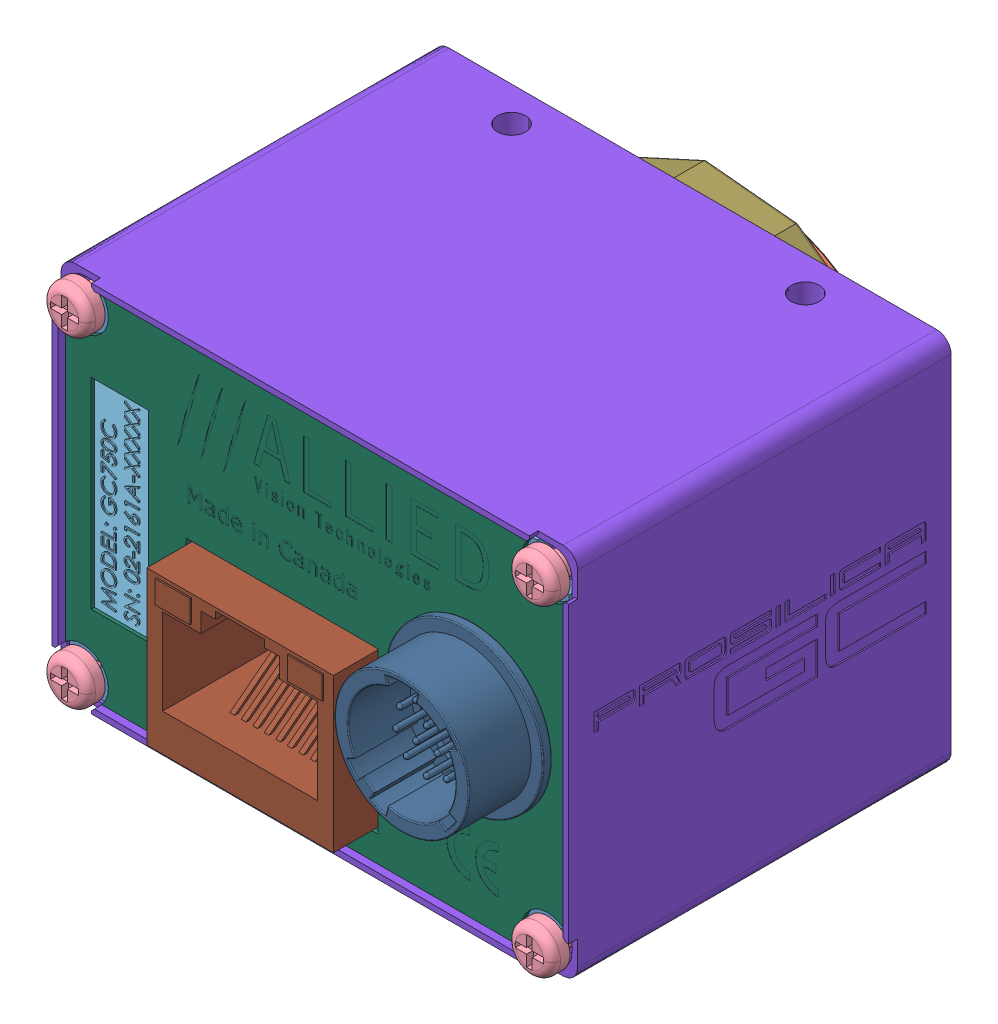
SolidWorks assembly Prosilica_GC750C, configuration Default. Lengths in mm.
Overall size (45.72 40.39 45.39).
25 component instances, 15 part files, 0 mates.
Components (placement in the parent):
- 110043A GC BACK PLATE-1: 110043A GC BACK PLATE [Default] at origin size (44.2 31.5 1.29)
  - 110043A GC BACK PLATE - WO HW-1: 110043A GC BACK PLATE - WO HW [Default] at origin size (44.2 31.5 1.29)
- 110039A-C ADJUSTABLE CS MOUNT RING-1: 110039A-C ADJUSTABLE CS MOUNT RING [Default] at (0 0 -28.7749) x (-0.743279 -0.668982 0) z (0 0 -1) size (27.78 27.78 8.64)
- 140018-SCREW PAN M2x8 SS-1: 140018-SCREW PAN M2x8 SS [Default] at (-17.145 0 -28.0747) x (-0.962983 0.269563 0) z (0 0 -1) size (4 4 9.7)
- 140017-SCREW PAN M2x4 SS-1: 140017-SCREW PAN M2x4 SS [Default] at (20.574 14.224 1.6713) size (4 4 5.6)
- 140018-SCREW PAN M2x8 SS-2: 140018-SCREW PAN M2x8 SS [Default] at (17.145 0 -28.0747) x (-0.840364 0.542023 0) z (0 0 -1) size (4 4 9.7)
- 740070AA-GC750C LABEL PRINT-1: 740070AA-GC750C LABEL PRINT [Default] at (-17.5822 0 1.2903) x (0 1 0) z (0 0 1) size (18.8 6.1 0.2)
- 100097A-IR FILTER ASSEMBLY 0.75 INCH-1: 100097A-IR FILTER ASSEMBLY 0.75 INCH [Default] at (0 0 -31.0392) x (-0.299434 -0.954117 0) z (0 0 -1) size (25.4 25.4 2.54)
  - 440002-IR CUT FILTER 22MM DIA-1: 440002-IR CUT FILTER 22MM DIA [Default] at (0 0 0.27) size (22 22 1)
  - 110054AB-IR FILTER SUPPORT-1: 110054AB-IR FILTER SUPPORT [Default] at origin size (25.4 25.4 2.54)
- 110047B-GC-CMOS FRONT_Finished with logo-1: 110047B-GC-CMOS FRONT_Finished with logo [Default] at (0 0 -31.7747) size (45.72 33.02 33.85)
- 140013-washer spring lock M2-1: 140013-washer spring lock M2 [Default] at (17.145 0 -28.0747) size (4.39 4.4 0.5)
- 260034-HIROSE HR10A-10R-12PB-1: 260034-HIROSE HR10A-10R-12PB [Default] at (13.97 0 2.4613) x (-1 0 0) z (0 0 -1) size (14 14 15.61)
- 140017-SCREW PAN M2x4 SS-2: 140017-SCREW PAN M2x4 SS [Default] at (-20.574 -14.224 1.6713) size (4 4 5.6)
- 200047A-A GC INTERFACE PCB ASSY-1: 200047A-A GC INTERFACE PCB ASSY [Default] at (0 0 -11.2845) size (18.29 13.59 19.94)
  - 260033-AMPHENOL RJHS-3381-1: 260033-AMPHENOL RJHS-3381 [Default] at (-2.921 -13.1445 8.7249) x (0 0 -1) z (0 1 0) size (19.94 18.29 13.59)
- 110040A-B LOCKING RING CS MOUNT-1: 110040A-B LOCKING RING CS MOUNT [Default] at (0 0 -31.7747) x (-0.909526 -0.415646 0) z (0 0 -1) size (30.48 30.48 3.81)
- 140017-SCREW PAN M2x4 SS-3: 140017-SCREW PAN M2x4 SS [Default] at (20.574 -14.224 1.6713) size (4 4 5.6)
- 140017-SCREW PAN M2x4 SS-4: 140017-SCREW PAN M2x4 SS [Default] at (-20.574 14.224 1.6713) size (4 4 5.6)
- 200020BA-PCB ASSEMBLY EC750C SENSOR-with sensor-1: 200020BA-PCB ASSEMBLY EC750C SENSOR-with sensor [Default] at (0 0 -23.6467) size (9 9 1.25)
  - 220046-MICRON MT9V022177ATC-1: 220046-MICRON MT9V022177ATC [Default] at (0 0 -0.3) x (1 0 0) z (0 0 -1) size (9 9 1.25)
    - MT9V022 WINDOW-1: MT9V022 WINDOW [Default] at (0 0 0.55) size (6.7 6.7 0.4)
    - MT9V022 PACKAGE-1: MT9V022 PACKAGE [Default] at origin size (9 9 1.25)
- 740032B-GC MAIN LABEL-1: 740032B-GC MAIN LABEL [Default] at (0 0 1.2903) size (44.2 31.5 0.38)
- 140013-washer spring lock M2-2: 140013-washer spring lock M2 [Default] at (-17.145 0 -28.0747) size (4.39 4.4 0.5)
